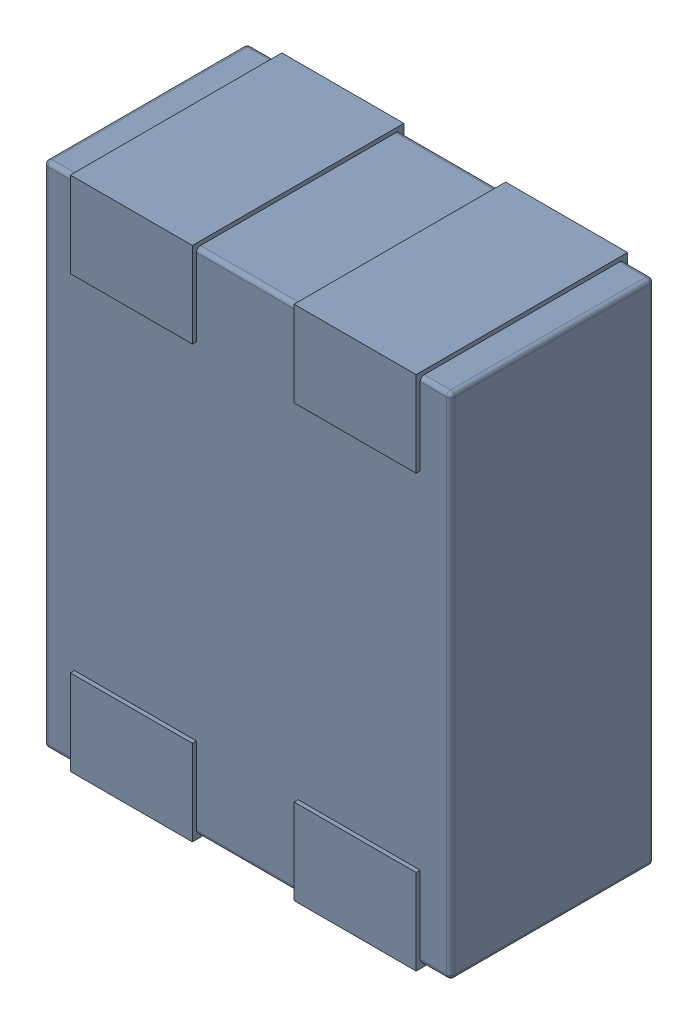
SolidWorks assembly L9, configuration Défaut. Lengths in mm.
Overall size (1 1.27 0.52).
4 component instances, 1 part files, 0 mates.
Components (placement in the parent):
- MCZ1210DH900L2TA0G-1: MCZ1210DH900L2TA0G [Défaut] at (40.722 -40.5265 -1.6) x (-1 0 0) z (0 0 1) size (1 1.27 0.52)
  - 3D_PCB1_2021-12-30 (1).step-1: 3D_PCB1_2021-12-30 (1).step [Défaut] at origin size (1 1.27 0.52)
    - a3ec64f90eb5404ebd79eca0046a794a.step-1: a3ec64f90eb5404ebd79eca0046a794a.step [Défaut] at (5.0419 -6.8961 1.6) size (1 1.27 0.52)
      - SOLID.step_650-1: SOLID.step_650 [Défaut] at origin size (1 1.27 0.52)
